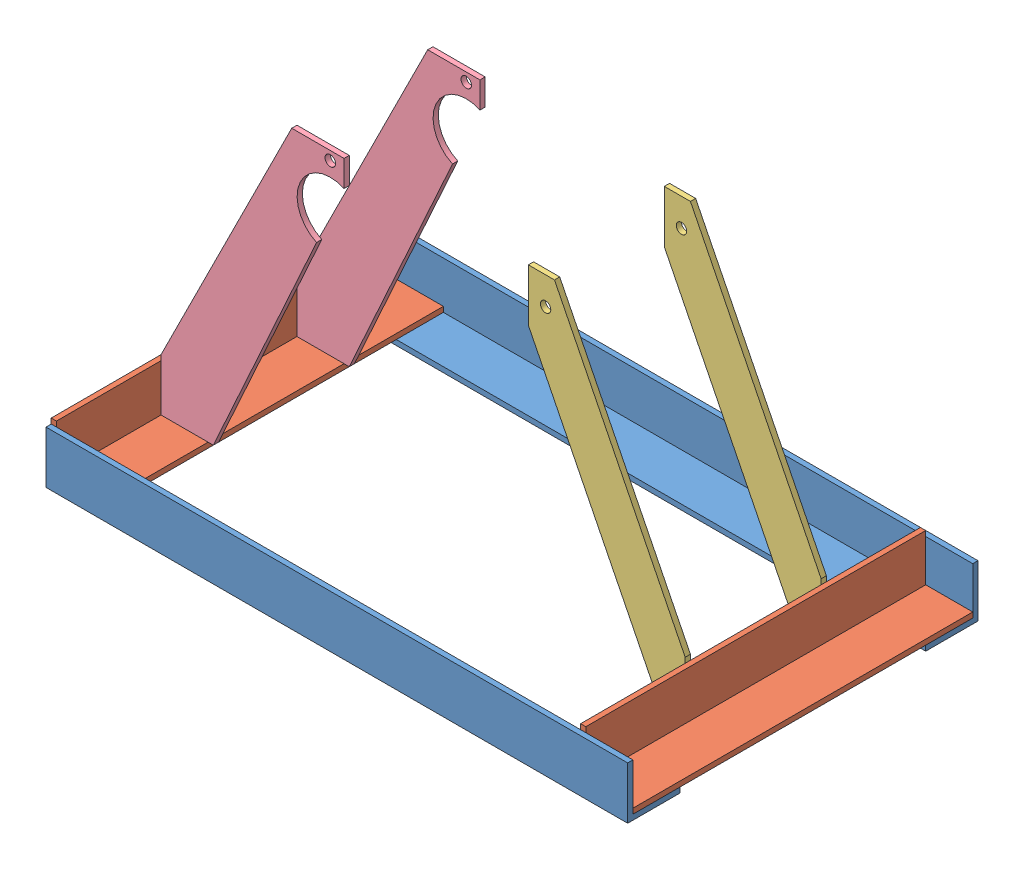
SolidWorks assembly Assem1, configuration Default. Lengths in mm.
Overall size (445 248 268).
8 component instances, 4 part files, 21 mates.
Components (placement in the parent):
- 1-1: 1 [Default] at (124.3776 150.328 405.6477) size (445 40 40)
- 2-1: 2 [Default] at (326.8776 154.328 519.6477) x (1 0 0) z (0 1 0) size (40 260 40)
- 3-1: 3 [Default] at (306.8776 241.6524 565.6477) size (120 240 4)
- 4-1: 4 [Default] at (-94.1224 198.328 461.6477) size (140 240 4)
- 1-2: 1 [Default] at (124.3776 150.328 633.6477) x (-1 0 0) z (0 0 -1) size (445 40 40)
- 2-2: 2 [Default] at (-98.1224 174.328 519.6477) x (0 1 0) z (1 0 0) size (40 260 40)
- 3-2: 3 [Default] at (306.8776 241.6524 461.6477) size (120 240 4)
- 4-2: 4 [Default] at (-94.1224 198.328 565.6477) size (140 240 4)
Mates (geometry in assembly coordinates):
- Coincident12: coincident anti-aligned: plane of 1-1 through (124.3776 154.328 405.6477) normal (0 1 0); plane of 2-2 through (-58.1224 154.328 519.6477) normal (0 -1 0)
- Coincident14: coincident anti-aligned: plane of 1-1 through (346.8776 190.328 389.6477) normal (0 0 1); plane of 2-2 through (-94.1224 174.328 389.6477) normal (0 0 -1)
- Coincident15: coincident aligned: line of 1-1 through (-98.1224 154.328 389.6477) axis (0 0 1); line of 2-2 through (-98.1224 154.328 389.6477) axis (0 0 1)
- Coincident16: coincident anti-aligned: plane of 1-1 through (124.3776 154.328 405.6477) normal (0 1 0); plane of 2-1 through (326.8776 154.328 519.6477) normal (0 -1 0)
- Coincident17: coincident anti-aligned: plane of 1-1 through (346.8776 190.328 389.6477) normal (0 0 1); plane of 2-1 through (326.8776 158.328 389.6477) normal (0 0 -1)
- Coincident18: coincident aligned: line of 1-1 through (346.8776 154.328 425.6477) axis (0 0 -1); line of 2-1 through (346.8776 154.328 649.6477) axis (0 0 -1)
- Coincident20: coincident anti-aligned: plane of 1-2 through (124.3776 154.328 633.6477) normal (0 1 0); plane of 2-2 through (-58.1224 154.328 519.6477) normal (0 -1 0)
- Coincident21: coincident anti-aligned: plane of 1-2 through (-98.1224 190.328 649.6477) normal (0 0 -1); plane of 2-2 through (-94.1224 174.328 649.6477) normal (0 0 1)
- Coincident22: coincident aligned: line of 1-2 through (-98.1224 154.328 613.6477) axis (0 0 1); line of 2-2 through (-98.1224 154.328 389.6477) axis (0 0 1)
- Coincident23: coincident anti-aligned: plane of 2-1 through (306.8776 194.328 519.6477) normal (-1 0 0); plane of 3-2 through (306.8776 158.328 242.5775) normal (1 0 0)
- Coincident24: coincident anti-aligned: plane of 2-1 through (306.8776 194.328 519.6477) normal (-1 0 0); plane of 3-1 through (306.8776 158.328 346.5775) normal (1 0 0)
- Coincident25: coincident anti-aligned: plane of 2-1 through (326.8776 158.328 519.6477) normal (0 1 0); plane of 3-1 through (306.8776 158.328 346.5775) normal (0 -1 0)
- Coincident26: coincident anti-aligned: plane of 2-1 through (326.8776 158.328 519.6477) normal (0 1 0); plane of 3-2 through (306.8776 158.328 242.5775) normal (0 -1 0)
- Coincident27: coincident anti-aligned: plane of 2-2 through (-94.1224 174.328 519.6477) normal (1 0 0); plane of 4-2 through (-94.1224 198.328 569.6477) normal (-1 0 0)
- Coincident28: coincident anti-aligned: plane of 4-1 through (-94.1224 198.328 465.6477) normal (-1 0 0); plane of 2-2 through (-94.1224 174.328 519.6477) normal (1 0 0)
- Coincident29: coincident anti-aligned: plane of 2-2 through (-58.1224 158.328 519.6477) normal (0 1 0); plane of 4-2 through (-94.1224 158.328 569.6477) normal (0 -1 0)
- Coincident30: coincident anti-aligned: plane of 4-1 through (-94.1224 158.328 465.6477) normal (0 -1 0); plane of 2-2 through (-58.1224 158.328 519.6477) normal (0 1 0)
- Distance2: distance = 100 mm anti-aligned: plane of 4-2 through (35.3733 355.2186 565.6477) normal (0 0 -1); plane of 4-1 through (35.3733 355.2186 465.6477) normal (0 0 1)
- Distance3: distance = 100 mm anti-aligned: plane of 3-1 through (306.8776 241.6524 565.6477) normal (0 0 -1); plane of 3-2 through (306.8776 241.6524 465.6477) normal (0 0 1)
- Distance5: distance = 80 mm anti-aligned: plane of 4-2 through (35.3733 355.2186 569.6477) normal (0 0 1); plane of 1-2 through (-98.1224 190.328 649.6477) normal (0 0 -1)
- Distance6: distance = 80 mm anti-aligned: plane of 3-1 through (306.8776 241.6524 569.6477) normal (0 0 1); plane of 1-2 through (-98.1224 190.328 649.6477) normal (0 0 -1)
